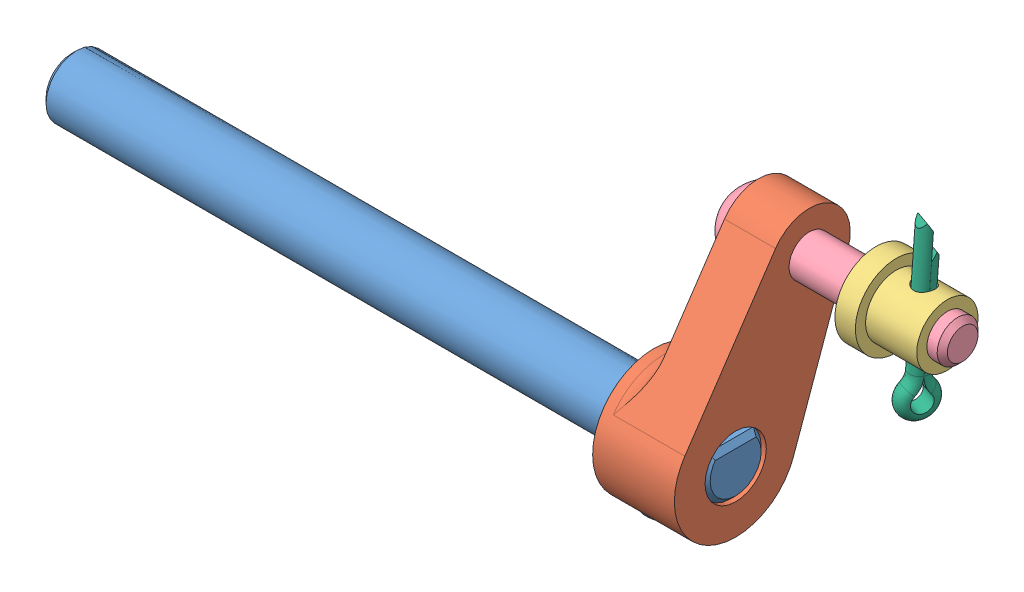
SolidWorks assembly 47.sub assembly crankshaft, configuration Default. Lengths in mm.
Overall size (80 31.16 23.41).
6 component instances, 6 part files, 10 mates.
Components (placement in the parent):
- 37.crankshaft rod-1: 37.crankshaft rod [Default] at (23.2641 33.8463 50.4705) size (65 6 6)
- 36.crankshaft roker-1: 36.crankshaft roker [Default] at (55.7641 33.8463 50.4705) x (0 -0.451163 -0.892442) z (0 0.892442 -0.451163) size (13.08 8 26)
- 38.crankshaft nut-1: 38.crankshaft nut [Default] at (65.7641 48.1254 43.2519) x (1 0 0) z (0 0.07788 0.996963) size (7 8 8)
- 39.crankshaft bolt-1: 39.crankshaft bolt [Default] at (50.7641 48.1254 43.2519) x (-1 0 0) z (0 0.996963 -0.07788) size (22.76 7 7)
- 1-1: 1 [DIN 913 - M3 x 3-S] at (50.7641 28.4917 53.1774) x (0 0.892442 -0.451163) z (-0.966918 0.115086 0.227652) size (3 3 3)
- split pin_din-1: split pin_din [DIN 94-2x10-C-St] at (66.7641 44.0832 43.5676) x (0 0.996963 -0.07788) z (-0.938495 -0.026891 -0.344244) size (16.5 3.6 1.8)
Mates (geometry in assembly coordinates):
- Concentric4: concentric anti-aligned: cylinder of 38.crankshaft nut-1 through (62.2641 48.1254 43.2519) axis (1 0 0) radius 2; cylinder of 39.crankshaft bolt-1 through (70.7641 48.1254 43.2519) axis (-1 0 0) radius 2
- Concentric5: concentric aligned: cylinder of 38.crankshaft nut-1 through (66.7641 44.1375 43.5634) axis (0 0.996963 -0.07788) radius 1; cylinder of 39.crankshaft bolt-1 through (66.7641 46.1315 43.4076) axis (0 0.996963 -0.07788) radius 1
- Concentric7: concentric aligned: cylinder of 36.crankshaft roker-1 through (50.7641 26.537 54.1656) axis (0 -0.892442 0.451163) radius 1.5; cylinder of socket set screw flat point_din-1 through (50.7641 17.1577 58.9072) axis (0 -0.892442 0.451163) radius 1.5
- Tangent1: tangent aligned: cylinder of 36.crankshaft roker-1 through (50.7641 33.8463 50.4705) axis (1 0 0) radius 6; plane of socket set screw flat point_din-1 through (50.7641 28.4917 53.1774) normal (0 -0.892442 0.451163)
- Concentric8: concentric aligned: cylinder of 38.crankshaft nut-1 through (66.7641 44.1375 43.5634) axis (0 0.996963 -0.07788) radius 1; cylinder of split pin_din-1 through (66.7641 44.0832 43.5676) axis (0 0.996963 -0.07788) radius 0.9
- Lock1: lock: unknown of 38.crankshaft nut-1; unknown of split pin_din-1
- Concentric9: concentric aligned: cylinder of 37.crankshaft rod-1 through (55.7641 33.8463 50.4705) axis (-1 0 0) radius 3; cylinder of 36.crankshaft roker-1 through (55.7641 33.8463 50.4705) axis (-1 0 0) radius 3
- Coincident5: coincident aligned: plane of 37.crankshaft rod-1 through (55.7641 33.8463 50.4705) normal (1 0 0); plane of 36.crankshaft roker-1 through (55.7641 33.8463 50.4705) normal (1 0 0)
- Concentric10: concentric anti-aligned: cylinder of 36.crankshaft roker-1 through (50.7641 48.1254 43.2519) axis (1 0 0) radius 2; cylinder of 39.crankshaft bolt-1 through (70.7641 48.1254 43.2519) axis (-1 0 0) radius 2
- Coincident6: coincident anti-aligned: plane of 36.crankshaft roker-1 through (50.7641 33.8463 50.4705) normal (-1 0 0); plane of 39.crankshaft bolt-1 through (50.7641 48.1254 43.2519) normal (1 0 0)
